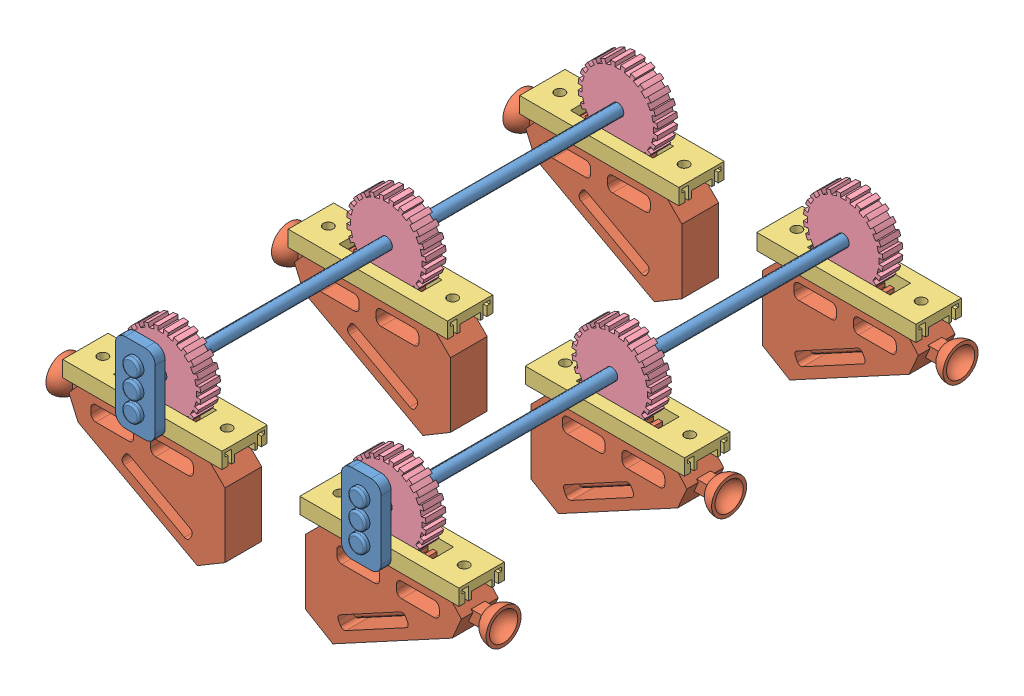
SolidWorks assembly TeamProject_RS_RetractingMechanism, configuration Default. Lengths in mm.
Overall size (442.55 180.19 522.66).
26 component instances, 4 part files, 17 mates.
Components (placement in the parent):
- TeamProject_RS_ControlAxle-1: TeamProject_RS_ControlAxle [Default] at (169.4755 279.5921 186.5831) size (40 80 521.3)
- TeamProject_RS_RetractingLegAssembly-1: TeamProject_RS_RetractingLegAssembly [Default] at (97.1928 102.3669 284.4948) size (182.12 180.09 45.6)
  - TeamProject_RS_LegMount-1: TeamProject_RS_LegMount [Default] at (126.7077 118.5254 127.4131) size (180.86 113.24 39)
  - TeamProject_RS_Rail-1: TeamProject_RS_Rail [Default] at (146.7077 137.2753 129.1131) x (0 0 1) z (-1 0 0) size (45.6 16 160)
  - TeamProject_RS_Gear-1: TeamProject_RS_Gear [Default] at (72.2827 177.2253 135.6131) size (79.81 79.81 20)
- TeamProject_RS_RetractingLegAssembly-2: TeamProject_RS_RetractingLegAssembly [Default] at (97.1928 102.3669 511.2105) size (182.12 180.09 45.6)
  - TeamProject_RS_LegMount-1: TeamProject_RS_LegMount [Default] at (126.7077 118.5254 127.4131) size (180.86 113.24 39)
  - TeamProject_RS_Rail-1: TeamProject_RS_Rail [Default] at (146.7077 137.2753 129.1131) x (0 0 1) z (-1 0 0) size (45.6 16 160)
  - TeamProject_RS_Gear-1: TeamProject_RS_Gear [Default] at (72.2827 177.2253 135.6131) size (79.81 79.81 20)
- TeamProject_RS_RetractingLegAssembly-3: TeamProject_RS_RetractingLegAssembly [Default] at (97.1928 102.3669 51.8055) size (182.12 180.09 45.6)
  - TeamProject_RS_LegMount-1: TeamProject_RS_LegMount [Default] at (126.7077 118.5254 127.4131) size (180.86 113.24 39)
  - TeamProject_RS_Rail-1: TeamProject_RS_Rail [Default] at (146.7077 137.2753 129.1131) x (0 0 1) z (-1 0 0) size (45.6 16 160)
  - TeamProject_RS_Gear-1: TeamProject_RS_Gear [Default] at (72.2827 177.2253 135.6131) size (79.81 79.81 20)
- TeamProject_RS_ControlAxle-2: TeamProject_RS_ControlAxle [Default] at (396.6436 279.5921 186.5831) size (40 80 521.3)
- TeamProject_RS_RetractingLegAssembly-4: TeamProject_RS_RetractingLegAssembly [Default] at (468.9263 102.3669 803.0367) x (-1 0 0) z (0 0 -1) size (182.12 180.09 45.6)
  - TeamProject_RS_LegMount-1: TeamProject_RS_LegMount [Default] at (126.7077 118.5254 127.4131) size (180.86 113.24 39)
  - TeamProject_RS_Rail-1: TeamProject_RS_Rail [Default] at (146.7077 137.2753 129.1131) x (0 0 1) z (-1 0 0) size (45.6 16 160)
  - TeamProject_RS_Gear-1: TeamProject_RS_Gear [Default] at (72.2827 177.2253 135.6131) size (79.81 79.81 20)
- TeamProject_RS_RetractingLegAssembly-5: TeamProject_RS_RetractingLegAssembly [Default] at (468.9263 102.3669 343.6317) x (-1 0 0) z (0 0 -1) size (182.12 180.09 45.6)
  - TeamProject_RS_LegMount-1: TeamProject_RS_LegMount [Default] at (126.7077 118.5254 127.4131) size (180.86 113.24 39)
  - TeamProject_RS_Rail-1: TeamProject_RS_Rail [Default] at (146.7077 137.2753 129.1131) x (0 0 1) z (-1 0 0) size (45.6 16 160)
  - TeamProject_RS_Gear-1: TeamProject_RS_Gear [Default] at (72.2827 177.2253 135.6131) size (79.81 79.81 20)
- TeamProject_RS_RetractingLegAssembly-6: TeamProject_RS_RetractingLegAssembly [Default] at (468.9263 102.3669 576.321) x (-1 0 0) z (0 0 -1) size (182.12 180.09 45.6)
  - TeamProject_RS_LegMount-1: TeamProject_RS_LegMount [Default] at (126.7077 118.5254 127.4131) size (180.86 113.24 39)
  - TeamProject_RS_Rail-1: TeamProject_RS_Rail [Default] at (146.7077 137.2753 129.1131) x (0 0 1) z (-1 0 0) size (45.6 16 160)
  - TeamProject_RS_Gear-1: TeamProject_RS_Gear [Default] at (72.2827 177.2253 135.6131) size (79.81 79.81 20)
Mates (geometry in assembly coordinates):
- Concentric1: concentric anti-aligned: cylinder of TeamProject_RS_ControlAxle-1 through (169.4755 279.5921 186.2831) axis (0 0 1) radius 5.85; cylinder of RSmain-1/TeamProject_RS_Gear-1 through (169.4755 279.5921 457.0785) axis (0 0 -1) radius 6
- Concentric2: concentric anti-aligned: cylinder of TeamProject_RS_ControlAxle-1 through (169.4755 279.5921 186.2831) axis (0 0 1) radius 5.85; cylinder of RSmain-2/TeamProject_RS_Gear-1 through (169.4755 279.5921 683.7941) axis (0 0 -1) radius 6
- Parallel1: parallel aligned: line of TeamProject_RS_ControlAxle-1 through (159.4755 239.5921 682.5831) axis (1 0 0); line of RSmain-2/TeamProject_RS_Rail-1 through (83.9005 255.6421 679.9236) axis (1 0 0)
- Parallel2: parallel aligned: line of TeamProject_RS_ControlAxle-1 through (159.4755 239.5921 682.5831) axis (1 0 0); line of RSmain-1/TeamProject_RS_Rail-1 through (83.9005 255.6421 453.2079) axis (1 0 0)
- Concentric4: concentric anti-aligned: cylinder of TeamProject_RS_ControlAxle-1 through (169.4755 279.5921 186.2831) axis (0 0 1) radius 5.85; cylinder of RSmain-3/TeamProject_RS_Gear-1 through (169.4755 279.5921 224.3892) axis (0 0 -1) radius 6
- Parallel3: parallel aligned: line of TeamProject_RS_ControlAxle-1 through (159.4755 239.5921 682.5831) axis (1 0 0); line of TeamProject_RS_RetractingLegAssembly-3/TeamProject_RS_Rail-1 through (83.9005 255.6421 220.5186) axis (1 0 0)
- Coincident2: coincident aligned: line of TeamProject_RS_ControlAxle-1 through (179.4755 319.5921 692.5831) axis (-1 0 0); line of TeamProject_RS_ControlAxle-2 through (406.6436 319.5921 692.5831) axis (-1 0 0)
- Coincident3: coincident aligned: line of TeamProject_RS_ControlAxle-1 through (179.4755 319.5921 682.5831) axis (-1 0 0); line of TeamProject_RS_ControlAxle-2 through (406.6436 319.5921 682.5831) axis (-1 0 0)
- Concentric5: concentric aligned: cylinder of TeamProject_RS_ControlAxle-2 through (396.6436 279.5921 186.2831) axis (0 0 1) radius 5.85; cylinder of TeamProject_RS_RetractingLegAssembly-4/TeamProject_RS_Gear-1 through (396.6436 279.5921 630.453) axis (0 0 1) radius 6
- Parallel4: parallel aligned: line of TeamProject_RS_ControlAxle-2 through (406.6436 319.5921 692.5831) axis (-1 0 0); line of TeamProject_RS_RetractingLegAssembly-4/TeamProject_RS_Rail-1 through (482.2186 255.6421 679.9236) axis (-1 0 0)
- Concentric6: concentric aligned: cylinder of TeamProject_RS_ControlAxle-2 through (396.6436 279.5921 186.2831) axis (0 0 1) radius 5.85; cylinder of TeamProject_RS_RetractingLegAssembly-5/TeamProject_RS_Gear-1 through (396.6436 279.5921 171.048) axis (0 0 1) radius 6
- Parallel5: parallel aligned: line of TeamProject_RS_ControlAxle-2 through (406.6436 319.5921 692.5831) axis (-1 0 0); line of TeamProject_RS_RetractingLegAssembly-5/TeamProject_RS_Rail-1 through (482.2186 255.6421 220.5186) axis (-1 0 0)
- Concentric7: concentric aligned: cylinder of TeamProject_RS_ControlAxle-2 through (396.6436 279.5921 186.2831) axis (0 0 1) radius 5.85; cylinder of TeamProject_RS_RetractingLegAssembly-6/TeamProject_RS_Gear-1 through (396.6436 279.5921 403.7373) axis (0 0 1) radius 6
- Parallel6: parallel aligned: line of TeamProject_RS_ControlAxle-2 through (406.6436 319.5921 692.5831) axis (-1 0 0); line of TeamProject_RS_RetractingLegAssembly-6/TeamProject_RS_Rail-1 through (482.2186 255.6421 453.2079) axis (-1 0 0)
- Coincident8: coincident anti-aligned: line of TeamProject_RS_RetractingLegAssembly-1/TeamProject_RS_Rail-1 through (83.9005 255.6421 407.6079) axis (1 0 0); line of TeamProject_RS_RetractingLegAssembly-6/TeamProject_RS_Rail-1 through (482.2186 255.6421 407.6079) axis (-1 0 0)
- Coincident9: coincident anti-aligned: line of TeamProject_RS_RetractingLegAssembly-3/TeamProject_RS_Rail-1 through (83.9005 255.6421 174.9186) axis (1 0 0); line of TeamProject_RS_RetractingLegAssembly-5/TeamProject_RS_Rail-1 through (482.2186 255.6421 174.9186) axis (-1 0 0)
- Coincident11: coincident anti-aligned: line of TeamProject_RS_RetractingLegAssembly-2/TeamProject_RS_Rail-1 through (83.9005 255.6421 634.3236) axis (1 0 0); line of TeamProject_RS_RetractingLegAssembly-4/TeamProject_RS_Rail-1 through (482.2186 255.6421 634.3236) axis (-1 0 0)
